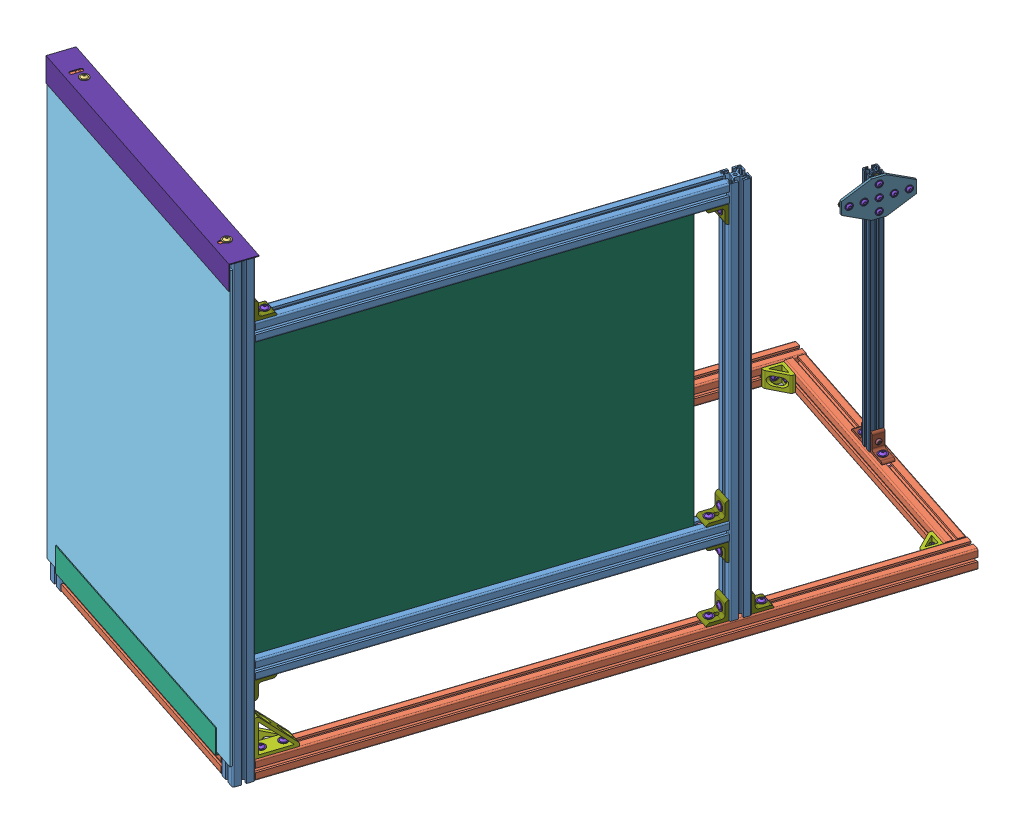
SolidWorks assembly SLATE_frame_3, configuration Default. Lengths in mm.
Overall size (972.96 971.2 1390.68).
245 component instances, 18 part files, 114 mates.
Components (placement in the parent):
- 650006-4: 650006 [38] at (-336.6278 -1446.6035 69.6702) x (-0.311561 0 0.950226) z (0 -1 0) size (38.1 38.1 965.2)
- 650006-5: 650006 [38] at (206.4264 -1446.6035 247.7274) x (0.311561 0 -0.950226) z (0 -1 0) size (38.1 38.1 965.2)
- 650005-1: 650005 [48] at (-330.6926 -1427.5535 51.5684) x (-0.950226 0 -0.311561) z (-0.311561 0 0.950226) size (38.1 38.1 1219.2)
- 650005-2: 650005 [48] at (212.3617 -1427.5535 229.6256) x (0.950226 0 0.311561) z (-0.311561 0 0.950226) size (38.1 38.1 1219.2)
- 650005-3: 650005 [21] at (568.18 -1427.5535 -916.7235) x (0.311561 0 -0.950226) z (0.950226 0 0.311561) size (38.1 38.1 533.4)
- 651134-1: 651134 [651134] at (169.257 -495.691 235.2566) size (17.14 20.29 17.14)
- 651134-2: 651134 [651134] at (-281.7033 -495.691 87.3952) size (17.14 20.29 17.14)
- 651097-1: 651097 [Default] at (-290.9857 -485.5691 92.8787) x (0.950226 0 0.311561) z (0 1 0) size (25.4 16.21 5.66)
- 651097-2: 651097 [Default] at (178.5395 -483.2422 229.7731) x (-0.950226 0 -0.311561) z (0 1 0) size (25.4 16.21 5.66)
- DISPLAY_ASSEMBLY-1: DISPLAY_ASSEMBLY [Default] at (217.1092 -1406.916 276.2899) x (-0.950226 0 -0.311561) z (0.311561 0 -0.950226) size (609.6 914.4 4.76)
- 650005-4: 650005 [21] at (188.3246 -500.4535 241.7922) x (0.311561 0 -0.950226) z (0.950226 0 0.311561) size (38.1 38.1 533.4)
- 650005-5: 650005 [21] at (188.3246 -1427.5535 241.7922) x (0.311561 0 -0.950226) z (0.950226 0 0.311561) size (38.1 38.1 533.4)
- 24_L_BRACKET-1: 24_L_BRACKET [Default] at (195.2293 -1408.5035 220.7338) x (-0.311561 0 0.950226) z (-0.950226 0 -0.311561) size (50.8 50.8 533.4)
- 653169-1: 653169 [653169 with 651129 (T-nuts)] at (196.5527 -1408.5035 224.4422) x (-0.950226 0 -0.311561) z (0 -1 0) size (33.27 89.02 89.02)
  - Inside Corner Gussets-1: Inside Corner Gussets [653169] at origin size (33.27 76.2 76.2)
  - 651129-1: 651129 [Default] at (-88.6646 325.6273 -34.3694) x (-0.259119 0.965845 0) z (-0.965845 -0.259119 0) size (28.73 20.29 22.23)
    - FBHSCS-1: FBHSCS [651134] at (-277.9712 -43.8944 0) size (17.14 20.29 17.14)
    - 651097-1: 651097 [Default] at (-286.9399 -41.8624 -5.983) x (0.965845 0 -0.259119) z (0 -1 0) size (25.4 16.21 5.66)
  - 651129-2: 651129 [Default] at (-88.6646 287.5273 -34.3694) x (-0.259119 0.965845 0) z (-0.965845 -0.259119 0) size (28.73 20.29 22.23)
    - FBHSCS-1: FBHSCS [651134] at (-277.9712 -43.8944 0) size (17.14 20.29 17.14)
    - 651097-1: 651097 [Default] at (-286.9399 -41.8624 -5.983) x (0.965845 0 -0.259119) z (0 -1 0) size (25.4 16.21 5.66)
  - 651129-3: 651129 [Default] at (55.3906 34.3694 -287.5273) x (0.259119 0 -0.965845) z (0.965845 0 0.259119) size (28.73 20.29 22.23)
    - FBHSCS-1: FBHSCS [651134] at (-277.9712 -43.8944 0) size (17.14 20.29 17.14)
    - 651097-1: 651097 [Default] at (-286.9399 -41.8624 -5.983) x (0.965845 0 -0.259119) z (0 -1 0) size (25.4 16.21 5.66)
  - 651129-4: 651129 [Default] at (55.3906 34.3694 -325.6273) x (0.259119 0 -0.965845) z (0.965845 0 0.259119) size (28.73 20.29 22.23)
    - FBHSCS-1: FBHSCS [651134] at (-277.9712 -43.8944 0) size (17.14 20.29 17.14)
    - 651097-1: 651097 [Default] at (-286.9399 -41.8624 -5.983) x (0.965845 0 -0.259119) z (0 -1 0) size (25.4 16.21 5.66)
- 653169-2: 653169 [653169 with 651129 (T-nuts)] at (-346.5015 -1408.5035 46.385) x (-0.950226 0 -0.311561) z (0 -1 0) size (33.27 89.02 89.02)
  - Inside Corner Gussets-1: Inside Corner Gussets [653169] at origin size (33.27 76.2 76.2)
  - 651129-1: 651129 [Default] at (-88.6646 325.6273 -34.3694) x (-0.259119 0.965845 0) z (-0.965845 -0.259119 0) size (28.73 20.29 22.23)
    - FBHSCS-1: FBHSCS [651134] at (-277.9712 -43.8944 0) size (17.14 20.29 17.14)
    - 651097-1: 651097 [Default] at (-286.9399 -41.8624 -5.983) x (0.965845 0 -0.259119) z (0 -1 0) size (25.4 16.21 5.66)
  - 651129-2: 651129 [Default] at (-88.6646 287.5273 -34.3694) x (-0.259119 0.965845 0) z (-0.965845 -0.259119 0) size (28.73 20.29 22.23)
    - FBHSCS-1: FBHSCS [651134] at (-277.9712 -43.8944 0) size (17.14 20.29 17.14)
    - 651097-1: 651097 [Default] at (-286.9399 -41.8624 -5.983) x (0.965845 0 -0.259119) z (0 -1 0) size (25.4 16.21 5.66)
  - 651129-3: 651129 [Default] at (55.3906 34.3694 -287.5273) x (0.259119 0 -0.965845) z (0.965845 0 0.259119) size (28.73 20.29 22.23)
    - FBHSCS-1: FBHSCS [651134] at (-277.9712 -43.8944 0) size (17.14 20.29 17.14)
    - 651097-1: 651097 [Default] at (-286.9399 -41.8624 -5.983) x (0.965845 0 -0.259119) z (0 -1 0) size (25.4 16.21 5.66)
  - 651129-4: 651129 [Default] at (55.3906 34.3694 -325.6273) x (0.259119 0 -0.965845) z (0.965845 0 0.259119) size (28.73 20.29 22.23)
    - FBHSCS-1: FBHSCS [651134] at (-277.9712 -43.8944 0) size (17.14 20.29 17.14)
    - 651097-1: 651097 [Default] at (-286.9399 -41.8624 -5.983) x (0.965845 0 -0.259119) z (0 -1 0) size (25.4 16.21 5.66)
- 653135-9: 653135 [653135 with 651129 (T-nut)] at (-318.4864 -519.5035 75.4848) x (0.311561 0 -0.950226) z (0 -1 0) size (33.27 89.02 89.02)
  - Inside Corner Brackets (STD)-1: Inside Corner Brackets (STD) [653135] at origin size (33.27 76.2 76.2)
  - 651129-1: 651129 [Default] at (-72.0276 34.3694 287.5273) x (-0.259119 0 0.965845) z (-0.965845 0 -0.259119) size (28.73 20.29 22.23)
    - FBHSCS-1: FBHSCS [651134] at (-277.9712 -43.8944 0) size (17.14 20.29 17.14)
    - 651097-1: 651097 [Default] at (-286.9399 -41.8624 -5.983) x (0.965845 0 -0.259119) z (0 -1 0) size (25.4 16.21 5.66)
  - 651129-2: 651129 [Default] at (72.0276 287.5273 34.3694) x (0.259119 0.965845 0) z (0.965845 -0.259119 0) size (28.73 20.29 22.23)
    - FBHSCS-1: FBHSCS [651134] at (-277.9712 -43.8944 0) size (17.14 20.29 17.14)
    - 651097-1: 651097 [Default] at (-286.9399 -41.8624 -5.983) x (0.965845 0 -0.259119) z (0 -1 0) size (25.4 16.21 5.66)
  - 651129-3: 651129 [Default] at (-72.0276 34.3694 325.6273) x (-0.259119 0 0.965845) z (-0.965845 0 -0.259119) size (28.73 20.29 22.23)
    - FBHSCS-1: FBHSCS [651134] at (-277.9712 -43.8944 0) size (17.14 20.29 17.14)
    - 651097-1: 651097 [Default] at (-286.9399 -41.8624 -5.983) x (0.965845 0 -0.259119) z (0 -1 0) size (25.4 16.21 5.66)
  - 651129-4: 651129 [Default] at (72.0276 325.6273 34.3694) x (0.259119 0.965845 0) z (0.965845 -0.259119 0) size (28.73 20.29 22.23)
    - FBHSCS-1: FBHSCS [651134] at (-277.9712 -43.8944 0) size (17.14 20.29 17.14)
    - 651097-1: 651097 [Default] at (-286.9399 -41.8624 -5.983) x (0.965845 0 -0.259119) z (0 -1 0) size (25.4 16.21 5.66)
- 653135-10: 653135 [653135 with 651129 (T-nut)] at (188.285 -519.5035 241.9129) x (-0.311561 0 0.950226) z (0 -1 0) size (33.27 89.02 89.02)
  - Inside Corner Brackets (STD)-1: Inside Corner Brackets (STD) [653135] at origin size (33.27 76.2 76.2)
  - 651129-1: 651129 [Default] at (-72.0276 34.3694 287.5273) x (-0.259119 0 0.965845) z (-0.965845 0 -0.259119) size (28.73 20.29 22.23)
    - FBHSCS-1: FBHSCS [651134] at (-277.9712 -43.8944 0) size (17.14 20.29 17.14)
    - 651097-1: 651097 [Default] at (-286.9399 -41.8624 -5.983) x (0.965845 0 -0.259119) z (0 -1 0) size (25.4 16.21 5.66)
  - 651129-2: 651129 [Default] at (72.0276 287.5273 34.3694) x (0.259119 0.965845 0) z (0.965845 -0.259119 0) size (28.73 20.29 22.23)
    - FBHSCS-1: FBHSCS [651134] at (-277.9712 -43.8944 0) size (17.14 20.29 17.14)
    - 651097-1: 651097 [Default] at (-286.9399 -41.8624 -5.983) x (0.965845 0 -0.259119) z (0 -1 0) size (25.4 16.21 5.66)
  - 651129-3: 651129 [Default] at (-72.0276 34.3694 325.6273) x (-0.259119 0 0.965845) z (-0.965845 0 -0.259119) size (28.73 20.29 22.23)
    - FBHSCS-1: FBHSCS [651134] at (-277.9712 -43.8944 0) size (17.14 20.29 17.14)
    - 651097-1: 651097 [Default] at (-286.9399 -41.8624 -5.983) x (0.965845 0 -0.259119) z (0 -1 0) size (25.4 16.21 5.66)
  - 651129-4: 651129 [Default] at (72.0276 325.6273 34.3694) x (0.259119 0.965845 0) z (0.965845 -0.259119 0) size (28.73 20.29 22.23)
    - FBHSCS-1: FBHSCS [651134] at (-277.9712 -43.8944 0) size (17.14 20.29 17.14)
    - 651097-1: 651097 [Default] at (-286.9399 -41.8624 -5.983) x (0.965845 0 -0.259119) z (0 -1 0) size (25.4 16.21 5.66)
- 650000-1: 650000 [20] at (308.3829 -1408.5035 -1001.906) x (0.311561 0 -0.950226) z (0 -1 0) size (25.4 25.4 508)
- 653268-1: 653268 [653268 with 655171 &651129 (T-nut)] at (296.2952 -1408.5035 -1005.8025) x (-0.311561 0 0.950226) z (-0.950226 0 -0.311561) size (28.92 49.2 49.32)
  - Inside Corner Brackets (TRAN)-1: Inside Corner Brackets (TRAN) [653268] at origin size (22.23 38.1 38.1)
  - 651171-1: 651171 [Default] at (5.7573 -134.239 -6.096) x (0 -1 0) z (0 0 -1) size (25.4 15.61 16.05)
    - 651163-1: 651163 [Default] at (-165.989 0.1693 0.5588) size (25.4 11.18 3.66)
    - 651021-1: 651021 [Default] at (-124.4615 -17.4041 104.1537) x (0 0 1) z (-0.626332 -0.779556 0) size (16.05 11.1 11.1)
      - Socket Button Head Cap Screw_AI-1: Socket Button Head Cap Screw_AI [SBHCSCREW 0.25-20x0.5-HX-C] at (-118.3777 36.9794 0) size (16.05 11.1 11.1)
  - 651129-1: 651129 [Default] at (-72.0276 32.7946 287.5273) x (-0.259119 0 0.965845) z (-0.965845 0 -0.259119) size (28.73 20.29 22.23)
    - FBHSCS-1: FBHSCS [651134] at (-277.9712 -43.8944 0) size (17.14 20.29 17.14)
    - 651097-1: 651097 [Default] at (-286.9399 -41.8624 -5.983) x (0.965845 0 -0.259119) z (0 -1 0) size (25.4 16.21 5.66)
- 653268-5: 653268 [653268 with 655171 &651129 (T-nut)] at (320.4705 -1408.5035 -998.0095) x (0.311561 0 -0.950226) z (0.950226 0 0.311561) size (28.92 49.2 49.32)
  - Inside Corner Brackets (TRAN)-1: Inside Corner Brackets (TRAN) [653268] at origin size (22.23 38.1 38.1)
  - 651171-1: 651171 [Default] at (5.7573 -134.239 -6.096) x (0 -1 0) z (0 0 -1) size (25.4 15.61 16.05)
    - 651163-1: 651163 [Default] at (-165.989 0.1693 0.5588) size (25.4 11.18 3.66)
    - 651021-1: 651021 [Default] at (-124.4615 -17.4041 104.1537) x (0 0 1) z (-0.626332 -0.779556 0) size (16.05 11.1 11.1)
      - Socket Button Head Cap Screw_AI-1: Socket Button Head Cap Screw_AI [SBHCSCREW 0.25-20x0.5-HX-C] at (-118.3777 36.9794 0) size (16.05 11.1 11.1)
  - 651129-1: 651129 [Default] at (-72.0276 32.7946 287.5273) x (-0.259119 0 0.965845) z (-0.965845 0 -0.259119) size (28.73 20.29 22.23)
    - FBHSCS-1: FBHSCS [651134] at (-277.9712 -43.8944 0) size (17.14 20.29 17.14)
    - 651097-1: 651097 [Default] at (-286.9399 -41.8624 -5.983) x (0.965845 0 -0.259119) z (0 -1 0) size (25.4 16.21 5.66)
- 653072-1: 653072 [653072 with 651130 (T-nut)] at (342.089 -900.5035 -1057.7475) x (-0.311561 0 0.950226) z (0.950226 0 0.311561) size (127 76.2 16)
  - Joining Plate (Cross)-1: Joining Plate (Cross) [653072] at origin size (127 76.2 4.78)
  - 651130-1: 651130 [Default] at (114.3 38.1 -7.9248) x (0 -1 0) z (-1 0 0) size (13.72 16 25.4)
    - FBHSCS-1: FBHSCS [651136] at origin size (13.72 16 13.72)
    - 651163-1: 651163 [Default] at (-5.588 1.27 12.7) x (0 0 -1) z (0 -1 0) size (25.4 11.18 3.66)
  - 651130-2: 651130 [Default] at (38.1 38.1 -7.9248) x (0 1 0) z (1 0 0) size (13.72 16 25.4)
    - FBHSCS-1: FBHSCS [651136] at origin size (13.72 16 13.72)
    - 651163-1: 651163 [Default] at (-5.588 1.27 12.7) x (0 0 -1) z (0 -1 0) size (25.4 11.18 3.66)
  - 651130-3: 651130 [Default] at (63.5 12.7 -7.9248) x (1 0 0) z (0 -1 0) size (13.72 16 25.4)
    - FBHSCS-1: FBHSCS [651136] at origin size (13.72 16 13.72)
    - 651163-1: 651163 [Default] at (-5.588 1.27 12.7) x (0 0 -1) z (0 -1 0) size (25.4 11.18 3.66)
  - 651130-4: 651130 [Default] at (88.9 38.1 -7.9248) x (0 -1 0) z (-1 0 0) size (13.72 16 25.4)
    - FBHSCS-1: FBHSCS [651136] at origin size (13.72 16 13.72)
    - 651163-1: 651163 [Default] at (-5.588 1.27 12.7) x (0 0 -1) z (0 -1 0) size (25.4 11.18 3.66)
  - 651130-5: 651130 [Default] at (63.5 38.1 -7.9248) x (-1 0 0) z (0 1 0) size (13.72 16 25.4)
    - FBHSCS-1: FBHSCS [651136] at origin size (13.72 16 13.72)
    - 651163-1: 651163 [Default] at (-5.588 1.27 12.7) x (0 0 -1) z (0 -1 0) size (25.4 11.18 3.66)
  - 651130-6: 651130 [Default] at (12.7 38.1 -7.9248) x (0 -1 0) z (-1 0 0) size (13.72 16 25.4)
    - FBHSCS-1: FBHSCS [651136] at origin size (13.72 16 13.72)
    - 651163-1: 651163 [Default] at (-5.588 1.27 12.7) x (0 0 -1) z (0 -1 0) size (25.4 11.18 3.66)
  - 651130-7: 651130 [Default] at (63.5 63.5 -7.9248) x (1 0 0) z (0 -1 0) size (13.72 16 25.4)
    - FBHSCS-1: FBHSCS [651136] at origin size (13.72 16 13.72)
    - 651163-1: 651163 [Default] at (-5.588 1.27 12.7) x (0 0 -1) z (0 -1 0) size (25.4 11.18 3.66)
- 653169-4: 653169 [653169 with 651129 (T-nuts)] at (-312.5907 -1410.9165 57.5036) x (0 1 0) z (-0.950226 0 -0.311561) size (33.27 89.02 89.02)
  - Inside Corner Gussets-1: Inside Corner Gussets [653169] at origin size (33.27 76.2 76.2)
  - 651129-1: 651129 [Default] at (-88.6646 325.6273 -34.3694) x (-0.259119 0.965845 0) z (-0.965845 -0.259119 0) size (28.73 20.29 22.23)
    - FBHSCS-1: FBHSCS [651134] at (-277.9712 -43.8944 0) size (17.14 20.29 17.14)
    - 651097-1: 651097 [Default] at (-286.9399 -41.8624 -5.983) x (0.965845 0 -0.259119) z (0 -1 0) size (25.4 16.21 5.66)
  - 651129-2: 651129 [Default] at (-88.6646 287.5273 -34.3694) x (-0.259119 0.965845 0) z (-0.965845 -0.259119 0) size (28.73 20.29 22.23)
    - FBHSCS-1: FBHSCS [651134] at (-277.9712 -43.8944 0) size (17.14 20.29 17.14)
    - 651097-1: 651097 [Default] at (-286.9399 -41.8624 -5.983) x (0.965845 0 -0.259119) z (0 -1 0) size (25.4 16.21 5.66)
  - 651129-3: 651129 [Default] at (55.3906 34.3694 -287.5273) x (0.259119 0 -0.965845) z (0.965845 0 0.259119) size (28.73 20.29 22.23)
    - FBHSCS-1: FBHSCS [651134] at (-277.9712 -43.8944 0) size (17.14 20.29 17.14)
    - 651097-1: 651097 [Default] at (-286.9399 -41.8624 -5.983) x (0.965845 0 -0.259119) z (0 -1 0) size (25.4 16.21 5.66)
  - 651129-4: 651129 [Default] at (55.3906 34.3694 -325.6273) x (0.259119 0 -0.965845) z (0.965845 0 0.259119) size (28.73 20.29 22.23)
    - FBHSCS-1: FBHSCS [651134] at (-277.9712 -43.8944 0) size (17.14 20.29 17.14)
    - 651097-1: 651097 [Default] at (-286.9399 -41.8624 -5.983) x (0.965845 0 -0.259119) z (0 -1 0) size (25.4 16.21 5.66)
- 653169-5: 653169 [653169 with 651129 (T-nuts)] at (193.5081 -1408.5035 225.9833) x (0.311561 0 -0.950226) z (0.950226 0 0.311561) size (33.27 89.02 89.02)
  - Inside Corner Gussets-1: Inside Corner Gussets [653169] at origin size (33.27 76.2 76.2)
  - 651129-1: 651129 [Default] at (-88.6646 325.6273 -34.3694) x (-0.259119 0.965845 0) z (-0.965845 -0.259119 0) size (28.73 20.29 22.23)
    - FBHSCS-1: FBHSCS [651134] at (-277.9712 -43.8944 0) size (17.14 20.29 17.14)
    - 651097-1: 651097 [Default] at (-286.9399 -41.8624 -5.983) x (0.965845 0 -0.259119) z (0 -1 0) size (25.4 16.21 5.66)
  - 651129-2: 651129 [Default] at (-88.6646 287.5273 -34.3694) x (-0.259119 0.965845 0) z (-0.965845 -0.259119 0) size (28.73 20.29 22.23)
    - FBHSCS-1: FBHSCS [651134] at (-277.9712 -43.8944 0) size (17.14 20.29 17.14)
    - 651097-1: 651097 [Default] at (-286.9399 -41.8624 -5.983) x (0.965845 0 -0.259119) z (0 -1 0) size (25.4 16.21 5.66)
  - 651129-3: 651129 [Default] at (55.3906 34.3694 -287.5273) x (0.259119 0 -0.965845) z (0.965845 0 0.259119) size (28.73 20.29 22.23)
    - FBHSCS-1: FBHSCS [651134] at (-277.9712 -43.8944 0) size (17.14 20.29 17.14)
    - 651097-1: 651097 [Default] at (-286.9399 -41.8624 -5.983) x (0.965845 0 -0.259119) z (0 -1 0) size (25.4 16.21 5.66)
  - 651129-4: 651129 [Default] at (55.3906 34.3694 -325.6273) x (0.259119 0 -0.965845) z (0.965845 0 0.259119) size (28.73 20.29 22.23)
    - FBHSCS-1: FBHSCS [651134] at (-277.9712 -43.8944 0) size (17.14 20.29 17.14)
    - 651097-1: 651097 [Default] at (-286.9399 -41.8624 -5.983) x (0.965845 0 -0.259119) z (0 -1 0) size (25.4 16.21 5.66)
- 653169-6: 653169 [653169 with 651129 (T-nuts)] at (194.2599 -1410.9165 223.6904) x (0 1 0) z (-0.311561 0 0.950226) size (33.27 89.02 89.02)
  - Inside Corner Gussets-1: Inside Corner Gussets [653169] at origin size (33.27 76.2 76.2)
  - 651129-1: 651129 [Default] at (-88.6646 325.6273 -34.3694) x (-0.259119 0.965845 0) z (-0.965845 -0.259119 0) size (28.73 20.29 22.23)
    - FBHSCS-1: FBHSCS [651134] at (-277.9712 -43.8944 0) size (17.14 20.29 17.14)
    - 651097-1: 651097 [Default] at (-286.9399 -41.8624 -5.983) x (0.965845 0 -0.259119) z (0 -1 0) size (25.4 16.21 5.66)
  - 651129-2: 651129 [Default] at (-88.6646 287.5273 -34.3694) x (-0.259119 0.965845 0) z (-0.965845 -0.259119 0) size (28.73 20.29 22.23)
    - FBHSCS-1: FBHSCS [651134] at (-277.9712 -43.8944 0) size (17.14 20.29 17.14)
    - 651097-1: 651097 [Default] at (-286.9399 -41.8624 -5.983) x (0.965845 0 -0.259119) z (0 -1 0) size (25.4 16.21 5.66)
  - 651129-3: 651129 [Default] at (55.3906 34.3694 -287.5273) x (0.259119 0 -0.965845) z (0.965845 0 0.259119) size (28.73 20.29 22.23)
    - FBHSCS-1: FBHSCS [651134] at (-277.9712 -43.8944 0) size (17.14 20.29 17.14)
    - 651097-1: 651097 [Default] at (-286.9399 -41.8624 -5.983) x (0.965845 0 -0.259119) z (0 -1 0) size (25.4 16.21 5.66)
  - 651129-4: 651129 [Default] at (55.3906 34.3694 -325.6273) x (0.259119 0 -0.965845) z (0.965845 0 0.259119) size (28.73 20.29 22.23)
    - FBHSCS-1: FBHSCS [651134] at (-277.9712 -43.8944 0) size (17.14 20.29 17.14)
    - 651097-1: 651097 [Default] at (-286.9399 -41.8624 -5.983) x (0.965845 0 -0.259119) z (0 -1 0) size (25.4 16.21 5.66)
- 653169-7: 653169 [653169 with 651129 (T-nuts)] at (-313.3425 -1408.5035 59.7965) x (0.311561 0 -0.950226) z (0 -1 0) size (33.27 89.02 89.02)
  - Inside Corner Gussets-1: Inside Corner Gussets [653169] at origin size (33.27 76.2 76.2)
  - 651129-1: 651129 [Default] at (-88.6646 325.6273 -34.3694) x (-0.259119 0.965845 0) z (-0.965845 -0.259119 0) size (28.73 20.29 22.23)
    - FBHSCS-1: FBHSCS [651134] at (-277.9712 -43.8944 0) size (17.14 20.29 17.14)
    - 651097-1: 651097 [Default] at (-286.9399 -41.8624 -5.983) x (0.965845 0 -0.259119) z (0 -1 0) size (25.4 16.21 5.66)
  - 651129-2: 651129 [Default] at (-88.6646 287.5273 -34.3694) x (-0.259119 0.965845 0) z (-0.965845 -0.259119 0) size (28.73 20.29 22.23)
    - FBHSCS-1: FBHSCS [651134] at (-277.9712 -43.8944 0) size (17.14 20.29 17.14)
    - 651097-1: 651097 [Default] at (-286.9399 -41.8624 -5.983) x (0.965845 0 -0.259119) z (0 -1 0) size (25.4 16.21 5.66)
  - 651129-3: 651129 [Default] at (55.3906 34.3694 -287.5273) x (0.259119 0 -0.965845) z (0.965845 0 0.259119) size (28.73 20.29 22.23)
    - FBHSCS-1: FBHSCS [651134] at (-277.9712 -43.8944 0) size (17.14 20.29 17.14)
    - 651097-1: 651097 [Default] at (-286.9399 -41.8624 -5.983) x (0.965845 0 -0.259119) z (0 -1 0) size (25.4 16.21 5.66)
  - 651129-4: 651129 [Default] at (55.3906 34.3694 -325.6273) x (0.259119 0 -0.965845) z (0.965845 0 0.259119) size (28.73 20.29 22.23)
    - FBHSCS-1: FBHSCS [651134] at (-277.9712 -43.8944 0) size (17.14 20.29 17.14)
    - 651097-1: 651097 [Default] at (-286.9399 -41.8624 -5.983) x (0.965845 0 -0.259119) z (0 -1 0) size (25.4 16.21 5.66)
- 653165-1: 653165 [653165 with 651129 (T-nuts)] at (562.2448 -1444.1905 -898.6216) x (0 -1 0) z (0.311561 0 -0.950226) size (33.27 50.92 50.92)
  - Inside Corner Gussets-1: Inside Corner Gussets [653165] at origin size (33.27 38.1 38.1)
  - 651129-1: 651129 [Default] at (55.3906 34.3694 -287.5273) x (0.259119 0 -0.965845) z (0.965845 0 0.259119) size (28.73 20.29 22.23)
    - FBHSCS-1: FBHSCS [651134] at (-277.9712 -43.8944 0) size (17.14 20.29 17.14)
    - 651097-1: 651097 [Default] at (-286.9399 -41.8624 -5.983) x (0.965845 0 -0.259119) z (0 -1 0) size (25.4 16.21 5.66)
  - 651129-2: 651129 [Default] at (-88.6646 287.5273 -34.3694) x (-0.259119 0.965845 0) z (-0.965845 -0.259119 0) size (28.73 20.29 22.23)
    - FBHSCS-1: FBHSCS [651134] at (-277.9712 -43.8944 0) size (17.14 20.29 17.14)
    - 651097-1: 651097 [Default] at (-286.9399 -41.8624 -5.983) x (0.965845 0 -0.259119) z (0 -1 0) size (25.4 16.21 5.66)
- 653165-2: 653165 [653165 with 651129 (T-nuts)] at (55.3942 -1410.9165 -1064.8084) x (0 1 0) z (0.311561 0 -0.950226) size (33.27 50.92 50.92)
  - Inside Corner Gussets-1: Inside Corner Gussets [653165] at origin size (33.27 38.1 38.1)
  - 651129-1: 651129 [Default] at (55.3906 34.3694 -287.5273) x (0.259119 0 -0.965845) z (0.965845 0 0.259119) size (28.73 20.29 22.23)
    - FBHSCS-1: FBHSCS [651134] at (-277.9712 -43.8944 0) size (17.14 20.29 17.14)
    - 651097-1: 651097 [Default] at (-286.9399 -41.8624 -5.983) x (0.965845 0 -0.259119) z (0 -1 0) size (25.4 16.21 5.66)
  - 651129-2: 651129 [Default] at (-88.6646 287.5273 -34.3694) x (-0.259119 0.965845 0) z (-0.965845 -0.259119 0) size (28.73 20.29 22.23)
    - FBHSCS-1: FBHSCS [651134] at (-277.9712 -43.8944 0) size (17.14 20.29 17.14)
    - 651097-1: 651097 [Default] at (-286.9399 -41.8624 -5.983) x (0.965845 0 -0.259119) z (0 -1 0) size (25.4 16.21 5.66)
- MIRROR-1: MIRROR [Default] at (445.9332 -1236.6725 -482.7408) x (-0.311561 0 0.950226) z (-0.950226 0 -0.311561) size (762 609.6 3.17)
- 650006-8: 650006 [31.5] at (461.6418 -1243.4035 -530.6503) x (-0.950226 0 -0.311561) z (0.311561 0 -0.950226) size (38.1 38.1 800.1)
- 650006-9: 650006 [31.5] at (212.3617 -620.3415 229.6256) x (-0.950226 0 -0.311561) z (-0.311561 0 0.950226) size (38.1 38.1 800.1)
- 650006-10: 650006 [31.75] at (467.577 -1408.5035 -548.7521) x (0.311561 0 -0.950226) z (0 -1 0) size (38.1 38.1 806.45)
- 653133-1: 653133 [653133 with 651129 (T-nut)] at (461.7624 -639.3915 -530.6107) x (0.950226 0 0.311561) z (0 -1 0) size (33.27 57.27 50.92)
  - Inside Corner Brackets (SLOT)-5: Inside Corner Brackets (SLOT) [653133] at origin size (33.27 38.1 38.1)
  - 651129-1: 651129 [Default] at (-72.0276 34.3694 287.5273) x (-0.259119 0 0.965845) z (-0.965845 0 -0.259119) size (28.73 20.29 22.23)
    - FBHSCS-1: FBHSCS [651134] at (-277.9712 -43.8944 0) size (17.14 20.29 17.14)
    - 651097-1: 651097 [Default] at (-286.9399 -41.8624 -5.983) x (0.965845 0 -0.259119) z (0 -1 0) size (25.4 16.21 5.66)
  - 651129-2: 651129 [Default] at (72.0276 293.8773 34.3694) x (0.259119 0.965845 0) z (0.965845 -0.259119 0) size (28.73 20.29 22.23)
    - FBHSCS-1: FBHSCS [651134] at (-277.9712 -43.8944 0) size (17.14 20.29 17.14)
    - 651097-1: 651097 [Default] at (-286.9399 -41.8624 -5.983) x (0.965845 0 -0.259119) z (0 -1 0) size (25.4 16.21 5.66)
- 653133-2: 653133 [653133 with 651129 (T-nut)] at (461.5211 -1224.3535 -530.6898) x (-0.950226 0 -0.311561) z (0 1 0) size (33.27 57.27 50.92)
  - Inside Corner Brackets (SLOT)-5: Inside Corner Brackets (SLOT) [653133] at origin size (33.27 38.1 38.1)
  - 651129-1: 651129 [Default] at (-72.0276 34.3694 287.5273) x (-0.259119 0 0.965845) z (-0.965845 0 -0.259119) size (28.73 20.29 22.23)
    - FBHSCS-1: FBHSCS [651134] at (-277.9712 -43.8944 0) size (17.14 20.29 17.14)
    - 651097-1: 651097 [Default] at (-286.9399 -41.8624 -5.983) x (0.965845 0 -0.259119) z (0 -1 0) size (25.4 16.21 5.66)
  - 651129-2: 651129 [Default] at (72.0276 293.8773 34.3694) x (0.259119 0.965845 0) z (0.965845 -0.259119 0) size (28.73 20.29 22.23)
    - FBHSCS-1: FBHSCS [651134] at (-277.9712 -43.8944 0) size (17.14 20.29 17.14)
    - 651097-1: 651097 [Default] at (-286.9399 -41.8624 -5.983) x (0.965845 0 -0.259119) z (0 -1 0) size (25.4 16.21 5.66)
- 653133-3: 653133 [653133 with 651129 (T-nut)] at (212.4823 -601.2915 229.6652) x (0.950226 0 0.311561) z (0 1 0) size (33.27 57.27 50.92)
  - Inside Corner Brackets (SLOT)-5: Inside Corner Brackets (SLOT) [653133] at origin size (33.27 38.1 38.1)
  - 651129-1: 651129 [Default] at (-72.0276 34.3694 287.5273) x (-0.259119 0 0.965845) z (-0.965845 0 -0.259119) size (28.73 20.29 22.23)
    - FBHSCS-1: FBHSCS [651134] at (-277.9712 -43.8944 0) size (17.14 20.29 17.14)
    - 651097-1: 651097 [Default] at (-286.9399 -41.8624 -5.983) x (0.965845 0 -0.259119) z (0 -1 0) size (25.4 16.21 5.66)
  - 651129-2: 651129 [Default] at (72.0276 293.8773 34.3694) x (0.259119 0.965845 0) z (0.965845 -0.259119 0) size (28.73 20.29 22.23)
    - FBHSCS-1: FBHSCS [651134] at (-277.9712 -43.8944 0) size (17.14 20.29 17.14)
    - 651097-1: 651097 [Default] at (-286.9399 -41.8624 -5.983) x (0.965845 0 -0.259119) z (0 -1 0) size (25.4 16.21 5.66)
- 653133-4: 653133 [653133 with 651129 (T-nut)] at (212.241 -1262.4535 229.5861) x (-0.950226 0 -0.311561) z (0 -1 0) size (33.27 57.27 50.92)
  - Inside Corner Brackets (SLOT)-5: Inside Corner Brackets (SLOT) [653133] at origin size (33.27 38.1 38.1)
  - 651129-1: 651129 [Default] at (-72.0276 34.3694 287.5273) x (-0.259119 0 0.965845) z (-0.965845 0 -0.259119) size (28.73 20.29 22.23)
    - FBHSCS-1: FBHSCS [651134] at (-277.9712 -43.8944 0) size (17.14 20.29 17.14)
    - 651097-1: 651097 [Default] at (-286.9399 -41.8624 -5.983) x (0.965845 0 -0.259119) z (0 -1 0) size (25.4 16.21 5.66)
  - 651129-2: 651129 [Default] at (72.0276 293.8773 34.3694) x (0.259119 0.965845 0) z (0.965845 -0.259119 0) size (28.73 20.29 22.23)
    - FBHSCS-1: FBHSCS [651134] at (-277.9712 -43.8944 0) size (17.14 20.29 17.14)
    - 651097-1: 651097 [Default] at (-286.9399 -41.8624 -5.983) x (0.965845 0 -0.259119) z (0 -1 0) size (25.4 16.21 5.66)
- 653133-5: 653133 [653133 with 651129 (T-nut)] at (461.5211 -1408.5035 -530.6898) x (-0.950226 0 -0.311561) z (0 1 0) size (33.27 57.27 50.92)
  - Inside Corner Brackets (SLOT)-5: Inside Corner Brackets (SLOT) [653133] at origin size (33.27 38.1 38.1)
  - 651129-1: 651129 [Default] at (-72.0276 34.3694 287.5273) x (-0.259119 0 0.965845) z (-0.965845 0 -0.259119) size (28.73 20.29 22.23)
    - FBHSCS-1: FBHSCS [651134] at (-277.9712 -43.8944 0) size (17.14 20.29 17.14)
    - 651097-1: 651097 [Default] at (-286.9399 -41.8624 -5.983) x (0.965845 0 -0.259119) z (0 -1 0) size (25.4 16.21 5.66)
  - 651129-2: 651129 [Default] at (72.0276 293.8773 34.3694) x (0.259119 0.965845 0) z (0.965845 -0.259119 0) size (28.73 20.29 22.23)
    - FBHSCS-1: FBHSCS [651134] at (-277.9712 -43.8944 0) size (17.14 20.29 17.14)
    - 651097-1: 651097 [Default] at (-286.9399 -41.8624 -5.983) x (0.965845 0 -0.259119) z (0 -1 0) size (25.4 16.21 5.66)
- 653133-6: 653133 [653133 with 651129 (T-nut)] at (473.6329 -1408.5035 -566.8143) x (0.950226 0 0.311561) z (0 1 0) size (33.27 57.27 50.92)
  - Inside Corner Brackets (SLOT)-5: Inside Corner Brackets (SLOT) [653133] at origin size (33.27 38.1 38.1)
  - 651129-1: 651129 [Default] at (-72.0276 34.3694 287.5273) x (-0.259119 0 0.965845) z (-0.965845 0 -0.259119) size (28.73 20.29 22.23)
    - FBHSCS-1: FBHSCS [651134] at (-277.9712 -43.8944 0) size (17.14 20.29 17.14)
    - 651097-1: 651097 [Default] at (-286.9399 -41.8624 -5.983) x (0.965845 0 -0.259119) z (0 -1 0) size (25.4 16.21 5.66)
  - 651129-2: 651129 [Default] at (72.0276 293.8773 34.3694) x (0.259119 0.965845 0) z (0.965845 -0.259119 0) size (28.73 20.29 22.23)
    - FBHSCS-1: FBHSCS [651134] at (-277.9712 -43.8944 0) size (17.14 20.29 17.14)
    - 651097-1: 651097 [Default] at (-286.9399 -41.8624 -5.983) x (0.965845 0 -0.259119) z (0 -1 0) size (25.4 16.21 5.66)
- 653133-7: 653133 [653133 with 651129 (T-nut)] at (461.5211 -1262.4535 -530.6898) x (-0.950226 0 -0.311561) z (-0.311561 0 0.950226) size (33.27 57.27 50.92)
  - Inside Corner Brackets (SLOT)-5: Inside Corner Brackets (SLOT) [653133] at origin size (33.27 38.1 38.1)
  - 651129-1: 651129 [Default] at (-72.0276 34.3694 287.5273) x (-0.259119 0 0.965845) z (-0.965845 0 -0.259119) size (28.73 20.29 22.23)
    - FBHSCS-1: FBHSCS [651134] at (-277.9712 -43.8944 0) size (17.14 20.29 17.14)
    - 651097-1: 651097 [Default] at (-286.9399 -41.8624 -5.983) x (0.965845 0 -0.259119) z (0 -1 0) size (25.4 16.21 5.66)
  - 651129-2: 651129 [Default] at (72.0276 293.8773 34.3694) x (0.259119 0.965845 0) z (0.965845 -0.259119 0) size (28.73 20.29 22.23)
    - FBHSCS-1: FBHSCS [651134] at (-277.9712 -43.8944 0) size (17.14 20.29 17.14)
    - 651097-1: 651097 [Default] at (-286.9399 -41.8624 -5.983) x (0.965845 0 -0.259119) z (0 -1 0) size (25.4 16.21 5.66)
- 650005-6: 650005 [21] at (-318.526 -1427.5535 75.6055) x (-0.311561 0 0.950226) z (-0.950226 0 -0.311561) size (38.1 38.1 533.4)
- 27_L_BRACKET-1: 27_L_BRACKET [Default] at (-346.8159 -479.816 39.5992) x (-0.311561 0 0.950226) z (0.950226 0 0.311561) size (50.8 50.8 609.6)
Mates (geometry in assembly coordinates):
- Coincident42: coincident anti-aligned: plane of 650005-2 through (194.2599 -1427.5535 223.6904) normal (-0.950226 0 -0.311561); plane of 650005-3 through (568.18 -1427.5535 -916.7235) normal (0.950226 0 0.311561)
- Coincident43: coincident aligned: plane of 650005-2; plane of 650005-3
- Coincident47: coincident aligned: plane of 650005-1 through (49.1628 -1427.5535 -1106.9472) normal (0.311561 0 -0.950226); plane of 650005-3 through (574.1153 -1427.5535 -934.8253) normal (0.311561 0 -0.950226)
- Concentric3: concentric anti-aligned: cylinder of 651134-2 through (-281.7033 -495.691 87.3952) axis (0 -1 0) radius 3.9688; cylinder of 651097-1 through (-281.7033 -483.5371 87.3952) axis (0 1 0) radius 3.9688
- Concentric4: concentric anti-aligned: cylinder of 651134-1 through (169.257 -495.691 235.2566) axis (0 -1 0) radius 3.9688; cylinder of 651097-2 through (169.257 -481.2102 235.2566) axis (0 1 0) radius 3.9688
- Coincident71: coincident anti-aligned: plane of 650006-4 through (-338.7013 -481.4035 89.0382) normal (-0.311561 0 0.950226); plane of DISPLAY_ASSEMBLY-1 through (218.593 -492.516 271.7645) normal (0.311561 0 -0.950226)
- Coincident73: coincident anti-aligned: plane of 650006-5; plane of 650005-4 through (188.3246 -500.4535 241.7922) normal (0.950226 0 0.311561)
- Coincident74: coincident aligned: plane of 650006-5; plane of 650005-4 through (188.3246 -500.4535 241.7922) normal (0.311561 0 -0.950226)
- Coincident75: coincident aligned: plane of 650006-5; plane of 650005-4
- Coincident76: coincident anti-aligned: plane of 650006-5; plane of 650005-5 through (188.3246 -1427.5535 241.7922) normal (0.950226 0 0.311561)
- Coincident77: coincident aligned: plane of 650006-5; plane of 650005-5 through (188.3246 -1427.5535 241.7922) normal (0.311561 0 -0.950226)
- Coincident80: coincident anti-aligned: plane of 650006-4 through (-317.2598 -481.4035 71.7437) normal (0.950226 0 0.311561); plane of 650005-4 through (-323.5116 -516.4555 90.811) normal (-0.950226 0 -0.311561)
- Coincident81: coincident aligned: plane of 650006-4 through (-316.5969 -481.4035 59.5314) normal (0 1 0); plane of 650005-4 through (-317.2598 -481.4035 71.7437) normal (0 1 0)
- Coincident82: coincident aligned: plane of 650006-4 through (-326.8308 -481.4035 52.8346) normal (0.311561 0 -0.950226); plane of 650005-4 through (-312.5907 -504.5175 57.5036) normal (0.311561 0 -0.950226)
- Coincident83: coincident aligned: plane of 650006-5 through (206.4264 -1446.6035 247.7274) normal (0 -1 0); plane of 650005-5
- Coincident84: coincident aligned: plane of 650006-4 through (-336.6278 -1446.6035 69.6702) normal (0 -1 0); plane of 650005-5
- Coincident85: coincident anti-aligned: plane of 650006-5; plane of 650005-2 through (212.3617 -1427.5535 229.6256) normal (-0.311561 0 0.950226)
- Coincident86: coincident aligned: plane of 650006-5 through (206.4264 -1446.6035 247.7274) normal (0 -1 0); plane of 650005-2
- Coincident87: coincident aligned: plane of 650006-5; plane of 650005-2 through (230.4635 -1427.5535 235.5609) normal (0.950226 0 0.311561)
- Coincident90: coincident aligned: plane of 650005-2 through (592.2171 -1427.5535 -928.89) normal (0.311561 0 -0.950226); plane of 650005-3 through (574.1153 -1427.5535 -934.8253) normal (0.311561 0 -0.950226)
- Coincident109: coincident aligned: plane of 650005-1; plane of 650005-3
- Coincident111: coincident anti-aligned: plane of 650005-1; plane of 650005-3 through (61.3294 -1427.5535 -1082.9102) normal (-0.950226 0 -0.311561)
- Coincident116: coincident anti-aligned: plane of 651097-1 through (-285.9368 -485.5691 77.4801) normal (0 1 0); plane of 650005-4 through (-322.2681 -485.5691 87.0184) normal (0 -1 0)
- Coincident122: coincident anti-aligned: plane of 650006-5 through (189.5908 -481.4035 237.9305) normal (-0.950226 0 -0.311561); plane of 24_L_BRACKET-1 through (195.2293 -1408.5035 220.7338) normal (0.950226 0 0.311561)
- Coincident144: coincident anti-aligned: plane of 650006-5; plane of 653169-1/Inside Corner Gussets-1
- Coincident145: coincident anti-aligned: plane of 650005-2; plane of 653169-1/Inside Corner Gussets-1 through (196.5527 -1408.5035 224.4422) normal (0 -1 0)
- Coincident146: coincident aligned: plane of 650006-5; plane of 653169-1/Inside Corner Gussets-1
- Coincident147: coincident anti-aligned: plane of 650006-4; plane of 653169-2/Inside Corner Gussets-1
- Coincident148: coincident anti-aligned: plane of 650005-1; plane of 653169-2/Inside Corner Gussets-1 through (-346.5015 -1408.5035 46.385) normal (0 -1 0)
- Coincident149: coincident anti-aligned: plane of 650006-4; plane of 653169-2/Inside Corner Gussets-1
- Coincident150: coincident anti-aligned: plane of 650006-4; plane of 653135-9/Inside Corner Brackets (STD)-1
- Coincident151: coincident anti-aligned: plane of 650005-4; plane of 653135-9/Inside Corner Brackets (STD)-1
- Coincident152: coincident anti-aligned: plane of 650006-4; plane of 653135-9/Inside Corner Brackets (STD)-1
- Coincident153: coincident anti-aligned: plane of 650006-5; plane of 653135-10/Inside Corner Brackets (STD)-1
- Coincident154: coincident anti-aligned: plane of 650005-4; plane of 653135-10/Inside Corner Brackets (STD)-1
- Coincident155: coincident anti-aligned: plane of 650006-5; plane of 653135-10/Inside Corner Brackets (STD)-1
- Coincident156: coincident anti-aligned: plane of 650005-3; plane of 650000-1 through (308.3829 -1408.5035 -1001.906) normal (0 -1 0)
- Coincident158: coincident aligned: plane of 650005-3 through (568.18 -1427.5535 -916.7235) normal (0.311561 0 -0.950226); plane of 650000-1
- Coincident160: coincident anti-aligned: plane of 650005-3; plane of 653268-1/Inside Corner Brackets (TRAN)-1
- Coincident161: coincident anti-aligned: plane of 650000-1; plane of 653268-1/Inside Corner Brackets (TRAN)-1 through (296.2952 -1408.5035 -1005.8025) normal (0.950226 0 0.311561)
- Coincident162: coincident anti-aligned: plane of 650005-3 through (568.18 -1427.5535 -916.7235) normal (0.311561 0 -0.950226); plane of 653268-1/Inside Corner Brackets (TRAN)-1 through (296.315 -1408.5035 -1005.8629) normal (-0.311561 0 0.950226)
- Coincident172: coincident anti-aligned: plane of 650005-3; plane of 653268-5/Inside Corner Brackets (TRAN)-1
- Coincident173: coincident anti-aligned: plane of 650000-1; plane of 653268-5/Inside Corner Brackets (TRAN)-1 through (320.4705 -1408.5035 -998.0095) normal (-0.950226 0 -0.311561)
- Coincident174: coincident aligned: plane of 650005-3 through (568.18 -1427.5535 -916.7235) normal (0.311561 0 -0.950226); plane of 653268-5/Inside Corner Brackets (TRAN)-1 through (320.4507 -1408.5035 -997.9492) normal (0.311561 0 -0.950226)
- Coincident185: coincident anti-aligned: plane of 650005-5 through (194.2599 -1427.5535 223.6904) normal (0.311561 0 -0.950226); plane of 653169-4/Inside Corner Gussets-1
- Coincident186: coincident anti-aligned: plane of 650005-1; plane of 653169-4/Inside Corner Gussets-1 through (-312.5907 -1410.9165 57.5036) normal (-0.950226 0 -0.311561)
- Coincident187: coincident anti-aligned: plane of 650005-5; plane of 653169-4/Inside Corner Gussets-1
- Coincident188: coincident anti-aligned: plane of 650005-5; plane of 653169-5/Inside Corner Gussets-1
- Coincident189: coincident anti-aligned: plane of 650006-5; plane of 653169-5/Inside Corner Gussets-1 through (193.5081 -1408.5035 225.9833) normal (0.950226 0 0.311561)
- Coincident190: coincident anti-aligned: plane of 650005-5 through (188.3246 -1427.5535 241.7922) normal (0.311561 0 -0.950226); plane of 653169-5/Inside Corner Gussets-1 through (188.3246 -1408.5035 241.7922) normal (-0.311561 0 0.950226)
- Coincident191: coincident anti-aligned: plane of 650005-2 through (194.2599 -1427.5535 223.6904) normal (-0.950226 0 -0.311561); plane of 653169-6/Inside Corner Gussets-1
- Coincident192: coincident anti-aligned: plane of 650005-5 through (194.2599 -1427.5535 223.6904) normal (0.311561 0 -0.950226); plane of 653169-6/Inside Corner Gussets-1 through (194.2599 -1410.9165 223.6904) normal (-0.311561 0 0.950226)
- Coincident193: coincident anti-aligned: plane of 650005-2; plane of 653169-6/Inside Corner Gussets-1
- Coincident194: coincident anti-aligned: plane of 650006-4; plane of 653169-7/Inside Corner Gussets-1
- Coincident195: coincident anti-aligned: plane of 650005-5; plane of 653169-7/Inside Corner Gussets-1 through (-313.3425 -1408.5035 59.7965) normal (0 -1 0)
- Coincident196: coincident aligned: plane of 650006-4; plane of 653169-7/Inside Corner Gussets-1
- Coincident197: coincident anti-aligned: plane of 650005-2 through (194.2599 -1427.5535 223.6904) normal (-0.950226 0 -0.311561); plane of 653165-1/Inside Corner Gussets-1
- Coincident198: coincident anti-aligned: plane of 650005-3 through (562.2448 -1427.5535 -898.6216) normal (-0.311561 0 0.950226); plane of 653165-1/Inside Corner Gussets-1 through (562.2448 -1444.1905 -898.6216) normal (0.311561 0 -0.950226)
- Coincident199: coincident aligned: plane of 650005-2; plane of 653165-1/Inside Corner Gussets-1
- Coincident200: coincident anti-aligned: plane of 650005-1; plane of 653165-2/Inside Corner Gussets-1
- Coincident201: coincident anti-aligned: plane of 650005-3 through (562.2448 -1427.5535 -898.6216) normal (-0.311561 0 0.950226); plane of 653165-2/Inside Corner Gussets-1 through (55.3942 -1410.9165 -1064.8084) normal (0.311561 0 -0.950226)
- Coincident202: coincident aligned: plane of 650005-1; plane of 653165-2/Inside Corner Gussets-1
- Coincident218: coincident anti-aligned: plane of 650006-5; plane of MIRROR-1 through (445.9332 -1236.6725 -482.7408) normal (-0.950226 0 -0.311561)
- Coincident220: coincident anti-aligned: plane of 650006-5 through (208.5235 -481.4035 241.3315) normal (0.311561 0 -0.950226); plane of MIRROR-1 through (205.5066 -1236.6725 240.3423) normal (-0.311561 0 0.950226)
- Coincident227: coincident anti-aligned: plane of 650006-5 through (216.2234 -481.4035 230.8918) normal (0.311561 0 -0.950226); plane of 650006-8 through (227.4465 -1259.2785 234.5717) normal (-0.311561 0 0.950226)
- Coincident228: coincident anti-aligned: plane of MIRROR-1 through (442.9162 -1236.6725 -483.73) normal (0 -1 0); plane of 650006-8 through (212.3617 -1236.6725 229.6256) normal (0 1 0)
- Coincident229: coincident anti-aligned: plane of 650006-5; plane of 650006-9 through (212.3617 -620.3415 229.6256) normal (-0.311561 0 0.950226)
- Coincident236: coincident anti-aligned: plane of 650006-5; plane of 650006-9
- Coincident242: coincident anti-aligned: plane of 650006-5; plane of 650006-8 through (461.6418 -1243.4035 -530.6503) normal (-0.950226 0 -0.311561)
- Coincident243: coincident anti-aligned: plane of MIRROR-1 through (442.9162 -627.0725 -483.73) normal (0 1 0); plane of 650006-9 through (461.6418 -627.0725 -530.6503) normal (0 -1 0)
- Distance2: distance = 184.15 mm aligned: plane of 650005-2; plane of 650006-8
- Coincident244: coincident anti-aligned: plane of 650005-2; plane of 650006-10 through (467.577 -1408.5035 -548.7521) normal (0 -1 0)
- Coincident248: coincident aligned: plane of 650005-2 through (212.3617 -1427.5535 229.6256) normal (0.950226 0 0.311561); plane of 650006-10
- Coincident249: coincident anti-aligned: plane of 650006-8 through (476.7266 -1259.2785 -525.7042) normal (0.311561 0 -0.950226); plane of 650006-10 through (465.5035 -602.0535 -529.3841) normal (-0.311561 0 0.950226)
- Coincident250: coincident anti-aligned: plane of 650006-10; plane of 653133-1/Inside Corner Brackets (SLOT)-5
- Coincident251: coincident anti-aligned: plane of 650006-9; plane of 653133-1/Inside Corner Brackets (SLOT)-5
- Coincident252: coincident aligned: plane of 650006-10; plane of 653133-1/Inside Corner Brackets (SLOT)-5
- Coincident253: coincident anti-aligned: plane of 650006-10; plane of 653133-2/Inside Corner Brackets (SLOT)-5
- Coincident254: coincident anti-aligned: plane of 650006-8; plane of 653133-2/Inside Corner Brackets (SLOT)-5
- Coincident255: coincident anti-aligned: plane of 650006-10; plane of 653133-2/Inside Corner Brackets (SLOT)-5
- Coincident256: coincident anti-aligned: plane of 650006-5; plane of 653133-3/Inside Corner Brackets (SLOT)-5
- Coincident257: coincident anti-aligned: plane of 650006-9; plane of 653133-3/Inside Corner Brackets (SLOT)-5
- Coincident258: coincident aligned: plane of 650006-5; plane of 653133-3/Inside Corner Brackets (SLOT)-5
- Coincident259: coincident anti-aligned: plane of 650006-5; plane of 653133-4/Inside Corner Brackets (SLOT)-5
- Coincident260: coincident anti-aligned: plane of 650006-8; plane of 653133-4/Inside Corner Brackets (SLOT)-5
- Coincident261: coincident anti-aligned: plane of 650006-5; plane of 653133-4/Inside Corner Brackets (SLOT)-5
- Coincident262: coincident anti-aligned: plane of 650006-10; plane of 653133-5/Inside Corner Brackets (SLOT)-5
- Coincident263: coincident anti-aligned: plane of 650005-2; plane of 653133-5/Inside Corner Brackets (SLOT)-5
- Coincident264: coincident anti-aligned: plane of 650006-10; plane of 653133-5/Inside Corner Brackets (SLOT)-5
- Coincident265: coincident anti-aligned: plane of 650006-10; plane of 653133-6/Inside Corner Brackets (SLOT)-5
- Coincident266: coincident anti-aligned: plane of 650005-2; plane of 653133-6/Inside Corner Brackets (SLOT)-5
- Coincident267: coincident aligned: plane of 650006-10; plane of 653133-6/Inside Corner Brackets (SLOT)-5
- Coincident268: coincident anti-aligned: plane of 650006-8; plane of 653133-7/Inside Corner Brackets (SLOT)-5
- Coincident269: coincident anti-aligned: plane of 650006-10; plane of 653133-7/Inside Corner Brackets (SLOT)-5 through (461.5211 -1262.4535 -530.6898) normal (0.311561 0 -0.950226)
- Coincident270: coincident aligned: plane of 650006-8 through (461.6418 -1243.4035 -530.6503) normal (-0.950226 0 -0.311561); plane of 653133-7/Inside Corner Brackets (SLOT)-5
- Concentric5: concentric aligned: cylinder of 24_L_BRACKET-1 through (170.2228 -1357.7035 235.857) axis (0 -1 0) radius 4.1021; cylinder of 653169-5/651129-3/FBHSCS-1 through (170.2228 -1418.0285 235.857) axis (0 -1 0) radius 3.9688
- Concentric6: concentric aligned: cylinder of 24_L_BRACKET-1 through (134.0192 -1357.7035 223.9865) axis (0 -1 0) radius 4.1021; cylinder of 653169-5/651129-4/FBHSCS-1 through (134.0192 -1418.0285 223.9865) axis (0 -1 0) radius 3.9688
- Coincident272: coincident aligned: plane of 650006-5 through (186.3955 -1446.6035 257.8662) normal (0 -1 0); plane of 650005-6 through (187.0584 -1446.6035 245.6539) normal (0 -1 0)
- Coincident273: coincident anti-aligned: plane of 650006-5 through (189.5908 -481.4035 237.9305) normal (-0.950226 0 -0.311561); plane of 650005-6 through (193.3102 -1443.5555 226.5867) normal (0.950226 0 0.311561)
- Coincident274: coincident anti-aligned: plane of 653169-4/Inside Corner Gussets-1 through (-312.5907 -1444.1905 57.5036) normal (-0.311561 0 0.950226); plane of 650005-6 through (194.2599 -1431.6175 223.6904) normal (0.311561 0 -0.950226)
- Coincident275: coincident anti-aligned: plane of 24_L_BRACKET-1 through (-311.6213 -1408.5035 54.547) normal (0 -1 0); plane of 650005-6 through (189.5908 -1408.5035 237.9305) normal (0 1 0)
- Coincident277: coincident anti-aligned: plane of DISPLAY_ASSEMBLY-1 through (218.593 -1406.916 271.7645) normal (0 -1 0); plane of 24_L_BRACKET-1 through (-326.954 -1406.916 101.31) normal (0 1 0)
- Coincident280: coincident anti-aligned: plane of DISPLAY_ASSEMBLY-1 through (217.1092 -492.516 276.2899) normal (-0.311561 0 0.950226); plane of 27_L_BRACKET-1 through (217.1092 -530.616 276.2899) normal (0.311561 0 -0.950226)
- Coincident281: coincident anti-aligned: plane of 650005-4 through (-319.7922 -481.4035 79.4672) normal (0 1 0); plane of 27_L_BRACKET-1 through (217.1092 -481.4035 276.2899) normal (0 -1 0)
- Coincident282: coincident aligned: plane of 650006-5 through (223.262 -481.4035 257.5244) normal (0.950226 0 0.311561); plane of 27_L_BRACKET-1 through (232.4419 -479.816 229.5269) normal (0.950226 0 0.311561)
- Coincident284: coincident anti-aligned: plane of 650000-1 through (315.4883 -900.5035 -990.3147) normal (-0.950226 0 -0.311561); plane of 653072-1/651130-7/651163-1 through (319.991 -951.3035 -1004.0475) normal (0.950226 0 0.311561)
- Coincident285: coincident aligned: plane of 650000-1 through (294.9221 -900.5035 -995.0928) normal (0 1 0); plane of 653072-1/Joining Plate (Cross)-1 through (330.7992 -900.5035 -1007.9882) normal (0 1 0)
- Coincident286: coincident aligned: plane of 653268-5/651171-1/651163-1 through (318.1567 -1376.7535 -1004.6489) normal (0.311561 0 -0.950226); plane of 653072-1/651130-3/651163-1 through (319.991 -900.5035 -1004.0475) normal (0.311561 0 -0.950226)
- Distance4: distance = 292.1 mm aligned: plane of 653072-1/Joining Plate (Cross)-1 through (307.0582 -862.4035 -935.581) normal (0.950226 0 0.311561); plane of 650005-2 through (610.3189 -1423.4895 -922.9548) normal (0.950226 0 0.311561)
- Coincident287: coincident aligned: plane of 650006-4 through (-355.9958 -481.4035 67.5967) normal (-0.950226 0 -0.311561); plane of DISPLAY_ASSEMBLY-1 through (-360.6648 -1406.916 81.8368) normal (-0.950226 0 -0.311561)
- Coincident289: coincident anti-aligned: plane of 651134-1 through (173.2258 -479.816 235.2566) normal (0 -1 0); plane of 27_L_BRACKET-1 through (232.4419 -479.816 229.5269) normal (0 1 0)
- Coincident290: coincident anti-aligned: plane of 651134-2 through (-277.7345 -479.816 87.3952) normal (0 -1 0); plane of 27_L_BRACKET-1 through (232.4419 -479.816 229.5269) normal (0 1 0)
- Coincident291: coincident aligned: plane of 651097-1 through (-290.9857 -489.2013 92.8787) normal (-0.311561 0 0.950226); plane of 651097-2 through (173.4906 -486.8744 245.1717) normal (-0.311561 0 0.950226)
- Tangent2: tangent: cylinder of 651134-1 through (169.257 -495.691 235.2566) axis (0 -1 0) radius 3.9688; line of 650005-4 through (-317.2055 -493.3415 71.5781) axis (0.950226 0 0.311561)
